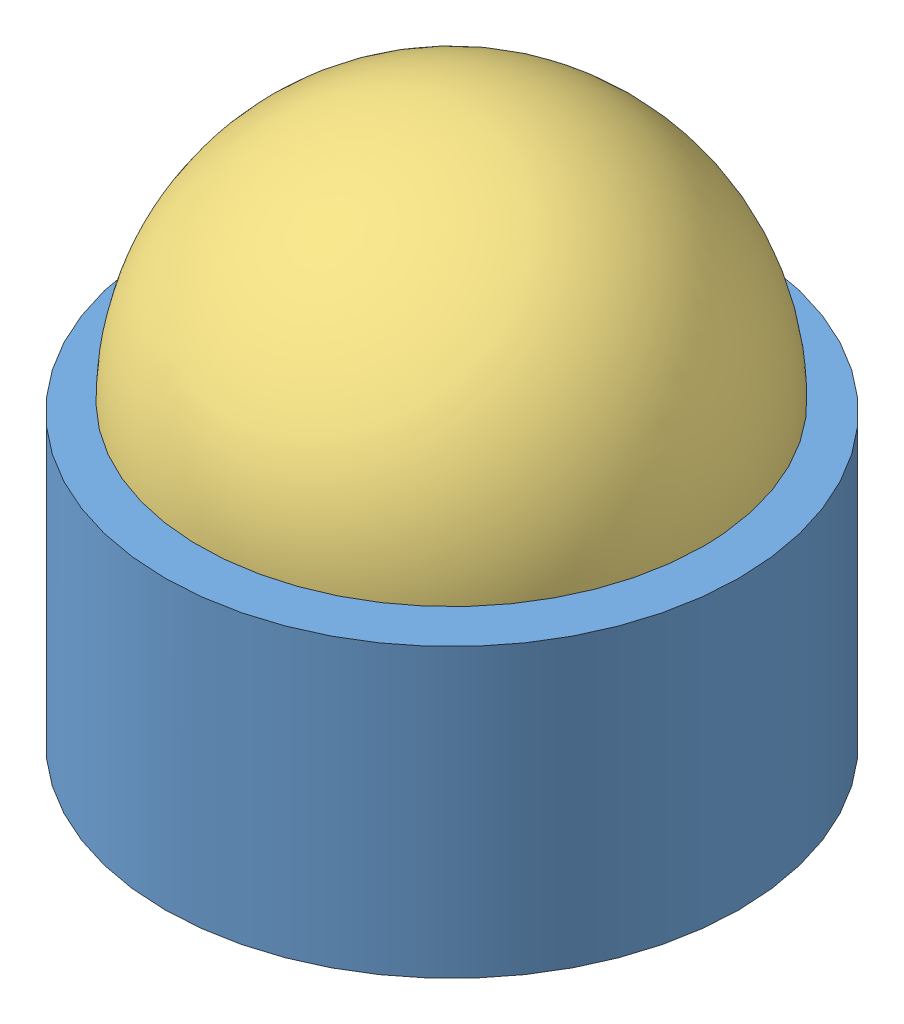
SolidWorks assembly Assem1, configuration Default. Lengths in mm.
Overall size (80 78.58 80).
5 component instances, 3 part files, 0 mates.
Components (placement in the parent):
- ButtonHousing-1: ButtonHousing [Default] at (31.9587 29.6261 68.5361) size (80 40 80)
- ButtonBase-1: ButtonBase [Default] at (-0.0421 29.6931 73.6884) size (5 2.5 5)
- ButtonTop-1: ButtonTop [Default] at (31.7329 70.7238 68.3825) size (70 47 70)
- ButtonBase-2: ButtonBase [Default] at (54.6019 29.6417 92.2712) size (5 2.5 5)
- ButtonBase-3: ButtonBase [Default] at (44.4436 29.764 36.0346) size (5 2.5 5)
